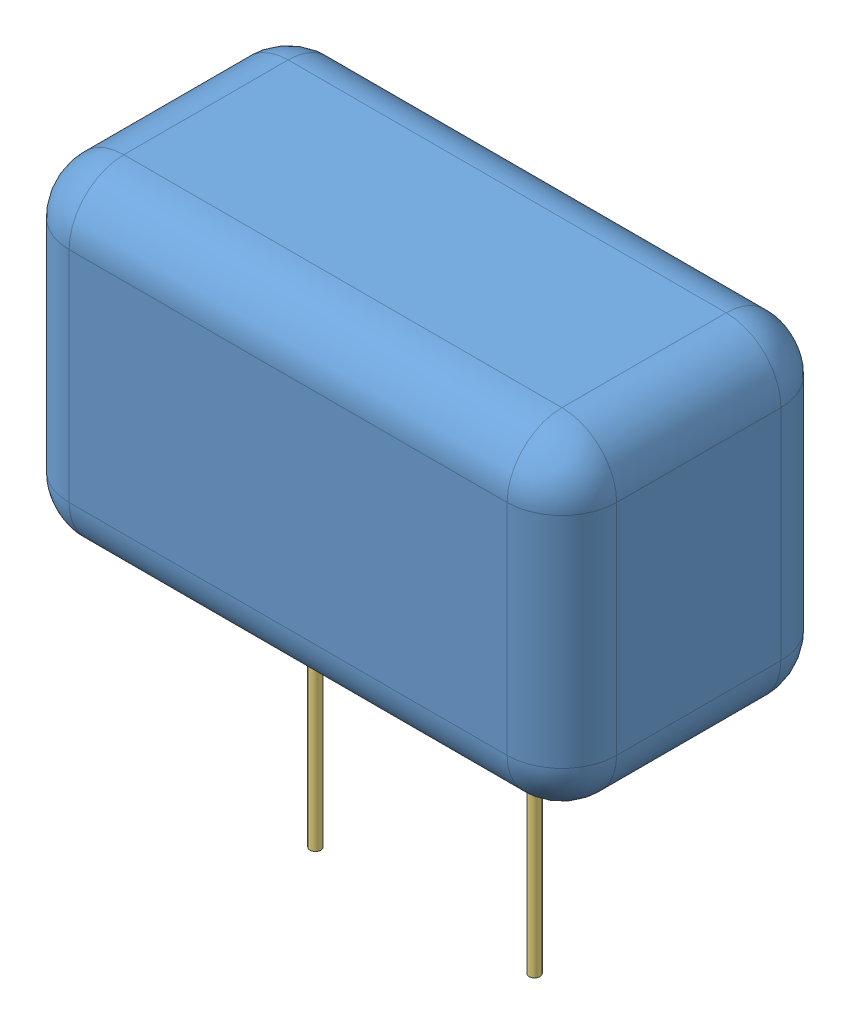
SolidWorks assembly Head Rest Assembly, configuration Default. Lengths in mm.
Overall size (254 271.78 127).
5 component instances, 3 part files, 14 mates.
Components (placement in the parent):
- Head Rest Cushion-1: Head Rest Cushion [Default] at origin size (254 152.4 127)
- Head Rest Connection-1: Head Rest Connection [Default] at (-50.8 -5.08 0) size (30.48 13.97 30.48)
- Head Rest Connection-2: Head Rest Connection [Default] at (50.8 -5.08 0) size (30.48 13.97 30.48)
- Head Rest Rod-1: Head Rest Rod [Default] at (-50.8 -119.38 0) x (-1 0 0) z (0 0 -1) size (5.08 127 5.08)
- Head Rest Rod-2: Head Rest Rod [Default] at (50.8 -119.38 0) size (5.08 127 5.08)
Mates (geometry in assembly coordinates):
- Coincident1: coordinate: point of Head Rest Cushion-1
- Coincident2: coincident aligned: plane of Head Rest Cushion-1 through (0 0 0) normal (0 1 0)
- Concentric1: concentric anti-aligned: circle of Head Rest Cushion-1; circle of Head Rest Connection-1
- Concentric2: concentric aligned: circle of Head Rest Cushion-1; circle of Head Rest Connection-2
- Coincident5: coincident anti-aligned: plane of Head Rest Cushion-1 through (-50.8 8.89 0) normal (0 -1 0); plane of Head Rest Connection-1 through (-50.8 8.89 0) normal (0 1 0)
- Coincident6: coincident anti-aligned: plane of Head Rest Cushion-1 through (50.8 8.89 0) normal (0 -1 0); plane of Head Rest Connection-2 through (50.8 8.89 0) normal (0 1 0)
- Parallel1: parallel aligned: plane of Head Rest Connection-1 through (-50.8 -5.08 0) normal (0 0 1)
- Parallel2: parallel aligned: plane of Head Rest Connection-2 through (50.8 -5.08 0) normal (0 0 1)
- Concentric3: concentric anti-aligned: circle of Head Rest Connection-1; circle of Head Rest Rod-1
- Concentric4: concentric anti-aligned: circle of Head Rest Connection-2; circle of Head Rest Rod-2
- Coincident11: coincident anti-aligned: plane of Head Rest Connection-2 through (50.8 7.62 0) normal (0 -1 0); circle of Head Rest Rod-2
- Coincident12: coincident anti-aligned: plane of Head Rest Connection-1 through (-50.8 7.62 0) normal (0 -1 0); plane of Head Rest Rod-1 through (-50.8 7.62 0) normal (0 1 0)
- Coincident13: coincident anti-aligned: plane of Head Rest Rod-1 through (-50.8 -119.38 0) normal (0 0 -1)
- Parallel3: parallel aligned: plane of Head Rest Rod-2 through (50.8 -119.38 0) normal (0 0 1)
